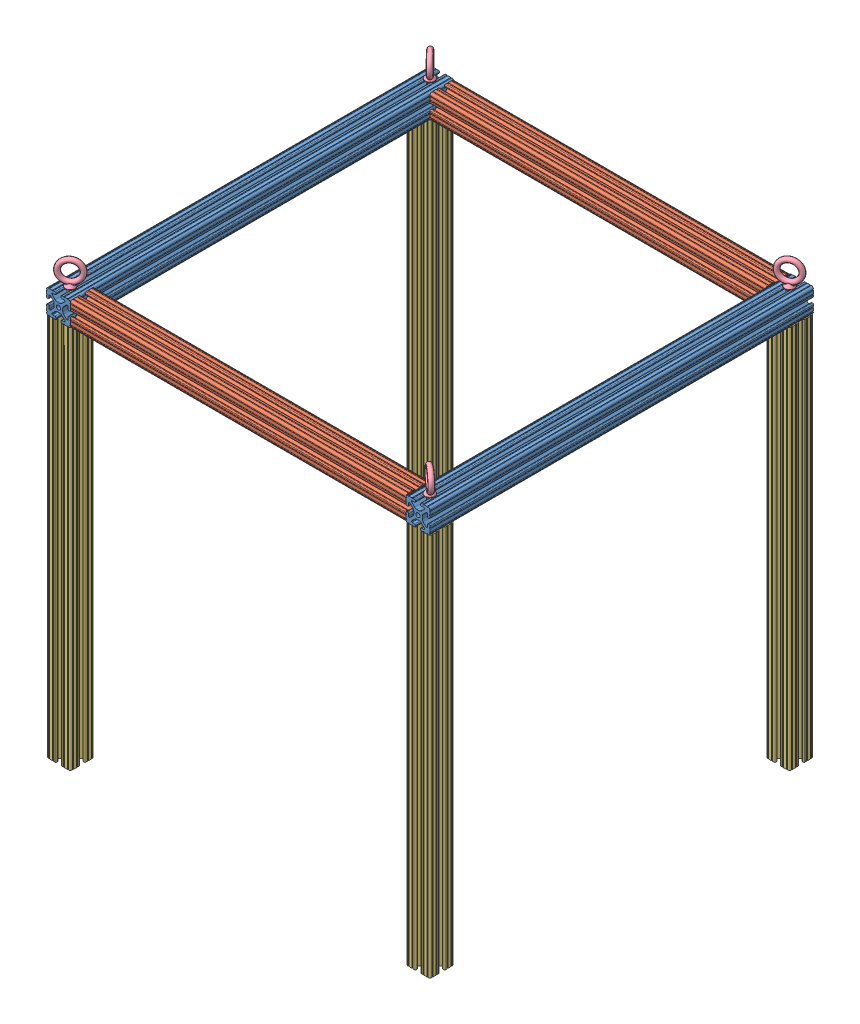
SolidWorks assembly T-Slot Superstructure, configuration Default. Lengths in mm.
Overall size (611.9 688.98 609.81).
12 component instances, 4 part files, 33 mates.
Components (placement in the parent):
- T-Slot Top Long-1: T-Slot Top Long [47065T21] at (82.9387 391.4039 494.442) size (38.1 38.1 609.6)
- T-Slot Top Long-2: T-Slot Top Long [47065T21] at (654.4387 391.4039 494.442) size (38.1 38.1 609.6)
- T-Slot Top Short-1: T-Slot Top Short [47065T21] at (368.6887 391.4039 780.192) x (0 0 -1) z (1 0 0) size (38.1 38.1 533.4)
- T-Slot Top Short-2: T-Slot Top Short [47065T21] at (368.6887 391.4039 208.692) x (0 0 1) z (-1 0 0) size (38.1 38.1 533.4)
- T-Slot Superstructure Upright-1: T-Slot Superstructure Upright [47065T21] at (82.9387 67.5539 208.692) x (1 0 0) z (0 1 0) size (38.1 38.1 609.6)
- T-Slot Superstructure Upright-2: T-Slot Superstructure Upright [47065T21] at (654.4387 67.5539 208.692) x (1 0 0) z (0 1 0) size (38.1 38.1 609.6)
- T-Slot Superstructure Upright-3: T-Slot Superstructure Upright [47065T21] at (654.4387 67.5539 780.192) x (1 0 0) z (0 1 0) size (38.1 38.1 609.6)
- T-Slot Superstructure Upright-4: T-Slot Superstructure Upright [47065T21] at (82.9387 67.5539 780.192) x (1 0 0) z (0 -1 0) size (38.1 38.1 609.6)
- 3014T257_STL EYEBOLT W SHLDR - FOR LIFTING-1: 3014T257_STL EYEBOLT W SHLDR - FOR LIFTING [3014T257] at (654.3434 432.6789 208.5967) x (0.877713 0 -0.479187) z (0.479187 0 0.877713) size (38.1 70.31 15.48)
- 3014T257_STL EYEBOLT W SHLDR - FOR LIFTING-2: 3014T257_STL EYEBOLT W SHLDR - FOR LIFTING [3014T257] at (82.8434 432.6789 780.2872) x (0.810238 0 -0.586101) z (0.586101 0 0.810238) size (38.1 70.31 15.48)
- 3014T257_STL EYEBOLT W SHLDR - FOR LIFTING-3: 3014T257_STL EYEBOLT W SHLDR - FOR LIFTING [3014T257] at (82.8434 432.6789 208.5967) x (0.68687 0 0.72678) z (-0.72678 0 0.68687) size (38.1 70.31 15.48)
- 3014T257_STL EYEBOLT W SHLDR - FOR LIFTING-4: 3014T257_STL EYEBOLT W SHLDR - FOR LIFTING [3014T257] at (654.3434 432.6789 780.2872) x (0.779635 0 0.626234) z (-0.626234 0 0.779635) size (38.1 70.31 15.48)
Mates (geometry in assembly coordinates):
- Coincident1: coincident anti-aligned: plane of T-Slot Top Long-1 through (101.9887 397.0215 799.242) normal (1 0 0); plane of T-Slot Top Short-1 through (101.9887 404.9563 789.5773) normal (-1 0 0)
- Coincident2: coincident aligned: plane of T-Slot Top Long-1 through (73.5534 404.9563 799.242) normal (0 0 1); plane of T-Slot Top Short-1 through (635.3887 399.3802 799.242) normal (0 0 1)
- Coincident3: coincident aligned: plane of T-Slot Top Long-1 through (90.9129 410.4539 799.242) normal (0 1 0); plane of T-Slot Top Short-1 through (635.3887 410.4539 785.8096) normal (0 1 0)
- Coincident4: coincident anti-aligned: plane of T-Slot Top Long-2 through (635.3887 399.3802 799.242) normal (-1 0 0); plane of T-Slot Top Short-1 through (635.3887 404.9563 789.5773) normal (1 0 0)
- Coincident5: coincident aligned: plane of T-Slot Top Long-2 through (645.0534 404.9563 799.242) normal (0 0 1); plane of T-Slot Top Short-1 through (635.3887 399.3802 799.242) normal (0 0 1)
- Coincident6: coincident aligned: plane of T-Slot Top Long-2 through (648.8211 410.4539 799.242) normal (0 1 0); plane of T-Slot Top Short-1 through (635.3887 410.4539 785.8096) normal (0 1 0)
- Coincident7: coincident anti-aligned: plane of T-Slot Top Long-1 through (101.9887 397.0215 799.242) normal (1 0 0); plane of T-Slot Top Short-2 through (101.9887 404.9563 199.3067) normal (-1 0 0)
- Coincident8: coincident aligned: plane of T-Slot Top Long-1 through (90.9129 410.4539 799.242) normal (0 1 0); plane of T-Slot Top Short-2 through (101.9887 410.4539 203.0743) normal (0 1 0)
- Coincident9: coincident aligned: plane of T-Slot Top Long-1 through (73.5534 404.9563 189.642) normal (0 0 -1); plane of T-Slot Top Short-2 through (101.9887 385.7863 189.642) normal (0 0 -1)
- Coincident10: coincident anti-aligned: plane of T-Slot Top Long-1 through (88.5563 372.3539 799.242) normal (0 -1 0); plane of T-Slot Superstructure Upright-4 through (73.5534 372.3539 793.7443) normal (0 1 0)
- Coincident11: coincident aligned: plane of T-Slot Top Long-1 through (73.5534 404.9563 799.242) normal (0 0 1); plane of T-Slot Superstructure Upright-4 through (90.9129 -237.2461 799.242) normal (0 0 1)
- Coincident12: coincident aligned: plane of T-Slot Top Long-1 through (63.8887 399.3802 799.242) normal (-1 0 0); plane of T-Slot Superstructure Upright-4 through (63.8887 -237.2461 788.1683) normal (-1 0 0)
- Coincident13: coincident anti-aligned: plane of T-Slot Top Long-1 through (74.9624 372.3539 799.242) normal (0 -1 0); plane of T-Slot Superstructure Upright-3 through (645.0534 372.3539 766.6396) normal (0 1 0)
- Coincident14: coincident anti-aligned: plane of T-Slot Top Long-1 through (74.9624 372.3539 799.242) normal (0 -1 0); plane of T-Slot Superstructure Upright-2 through (645.0534 372.3539 195.1396) normal (0 1 0)
- Coincident15: coincident anti-aligned: plane of T-Slot Top Short-2 through (101.9887 372.3539 214.3096) normal (0 -1 0); plane of T-Slot Superstructure Upright-1 through (73.5534 372.3539 195.1396) normal (0 1 0)
- Coincident16: coincident aligned: plane of T-Slot Top Long-1 through (63.8887 385.7863 799.242) normal (-1 0 0); plane of T-Slot Superstructure Upright-1 through (63.8887 372.3539 200.7156) normal (-1 0 0)
- Coincident17: coincident aligned: plane of T-Slot Top Long-1 through (73.5534 404.9563 189.642) normal (0 0 -1); plane of T-Slot Superstructure Upright-1 through (77.3211 372.3539 189.642) normal (0 0 -1)
- Coincident18: coincident aligned: plane of T-Slot Top Long-2 through (673.4887 383.4276 799.242) normal (1 0 0); plane of T-Slot Superstructure Upright-3 through (673.4887 372.3539 788.1683) normal (1 0 0)
- Coincident19: coincident aligned: plane of T-Slot Top Long-2 through (645.0534 404.9563 799.242) normal (0 0 1); plane of T-Slot Superstructure Upright-3 through (660.0563 372.3539 799.242) normal (0 0 1)
- Coincident20: coincident aligned: plane of T-Slot Top Long-2 through (645.0534 404.9563 189.642) normal (0 0 -1); plane of T-Slot Superstructure Upright-2 through (662.4129 372.3539 189.642) normal (0 0 -1)
- Coincident21: coincident aligned: plane of T-Slot Top Long-2 through (673.4887 383.4276 799.242) normal (1 0 0); plane of T-Slot Superstructure Upright-2 through (673.4887 372.3539 203.0743) normal (1 0 0)
- Coincident22: coincident anti-aligned: plane of T-Slot Top Long-2 through (662.4129 410.4539 799.242) normal (0 1 0); plane of 3014T257_STL EYEBOLT W SHLDR - FOR LIFTING-3 through (78.2092 410.4539 203.6932) normal (0 -1 0)
- Coincident23: coincident anti-aligned: plane of T-Slot Top Long-2 through (662.4129 410.4539 799.242) normal (0 1 0); plane of 3014T257_STL EYEBOLT W SHLDR - FOR LIFTING-4 through (649.0833 410.4539 776.0621) normal (0 -1 0)
- Coincident24: coincident anti-aligned: plane of T-Slot Top Long-2 through (662.4129 410.4539 799.242) normal (0 1 0); plane of 3014T257_STL EYEBOLT W SHLDR - FOR LIFTING-1 through (648.4216 410.4539 211.8297) normal (0 -1 0)
- Coincident25: coincident anti-aligned: plane of T-Slot Top Long-2 through (662.4129 410.4539 799.242) normal (0 1 0); plane of 3014T257_STL EYEBOLT W SHLDR - FOR LIFTING-2 through (77.3769 410.4539 784.2416) normal (0 -1 0)
- Tangent1: tangent anti-aligned: plane of T-Slot Top Long-2 through (650.3747 407.9435 799.242) normal (1 0 0); cylinder of 3014T257_STL EYEBOLT W SHLDR - FOR LIFTING-1 through (654.3434 381.8789 208.5967) axis (0 1 0) radius 3.9688
- Tangent2: tangent anti-aligned: plane of T-Slot Top Short-2 through (101.9887 407.9435 204.628) normal (0 0 1); cylinder of 3014T257_STL EYEBOLT W SHLDR - FOR LIFTING-1 through (654.3434 381.8789 208.5967) axis (0 1 0) radius 3.9688
- Tangent3: tangent anti-aligned: plane of T-Slot Top Long-2 through (650.3747 407.9435 799.242) normal (1 0 0); cylinder of 3014T257_STL EYEBOLT W SHLDR - FOR LIFTING-4 through (654.3434 381.8789 780.2872) axis (0 1 0) radius 3.9688
- Tangent4: tangent anti-aligned: plane of T-Slot Top Short-1 through (635.3887 407.9435 784.256) normal (0 0 -1); cylinder of 3014T257_STL EYEBOLT W SHLDR - FOR LIFTING-4 through (654.3434 381.8789 780.2872) axis (0 1 0) radius 3.9688
- Tangent5: tangent anti-aligned: plane of T-Slot Top Long-1 through (78.8747 407.9435 799.242) normal (1 0 0); cylinder of 3014T257_STL EYEBOLT W SHLDR - FOR LIFTING-2 through (82.8434 381.8789 780.2872) axis (0 1 0) radius 3.9688
- Tangent6: tangent anti-aligned: plane of T-Slot Top Long-1 through (78.8747 407.9435 799.242) normal (1 0 0); cylinder of 3014T257_STL EYEBOLT W SHLDR - FOR LIFTING-3 through (82.8434 381.8789 208.5967) axis (0 1 0) radius 3.9688
- Tangent7: tangent anti-aligned: plane of T-Slot Top Short-2 through (101.9887 407.9435 204.628) normal (0 0 1); cylinder of 3014T257_STL EYEBOLT W SHLDR - FOR LIFTING-3 through (82.8434 381.8789 208.5967) axis (0 1 0) radius 3.9688
- Tangent8: tangent anti-aligned: plane of T-Slot Top Short-1 through (635.3887 407.9435 784.256) normal (0 0 -1); cylinder of 3014T257_STL EYEBOLT W SHLDR - FOR LIFTING-2 through (82.8434 381.8789 780.2872) axis (0 1 0) radius 3.9688
